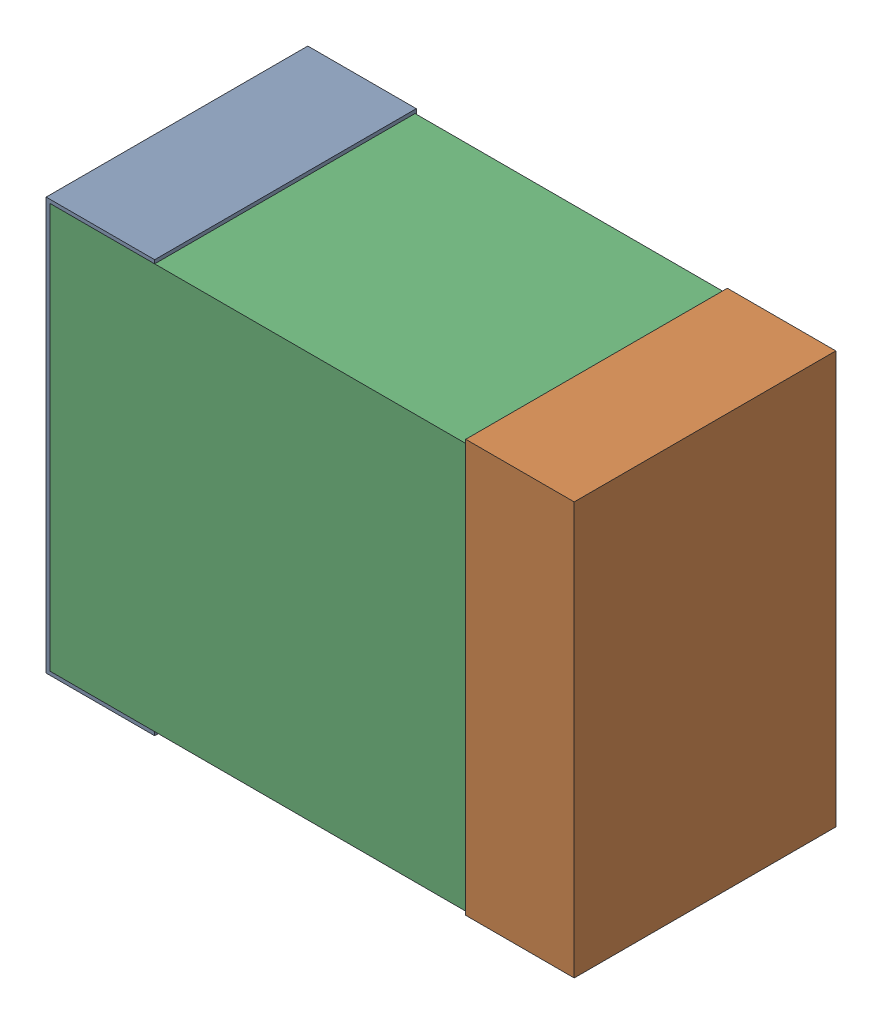
SolidWorks assembly CoutPwrPKanaloa_v2.0.0_Power, configuration Default. Lengths in mm.
Overall size (3.65 2.85 1.81).
6 component instances, 2 part files, 0 mates.
Components (placement in the parent):
- 334788400-1: 334788400 [Default] at (99.2102 58.42 -2.9108) size (0.75 2.85 1.81)
  - Extruded_5-1: Extruded_5 [Default] at origin size (0.75 2.85 1.81)
- 334788400-2: 334788400 [Default] at (102.1102 58.42 -2.9108) size (0.75 2.85 1.81)
  - Extruded_5-1: Extruded_5 [Default] at origin size (0.75 2.85 1.81)
- 334788784-1: 334788784 [Default] at (100.6602 58.42 -2.9024) size (3.6 2.8 1.8)
  - Extruded_6-1: Extruded_6 [Default] at origin size (3.6 2.8 1.8)
